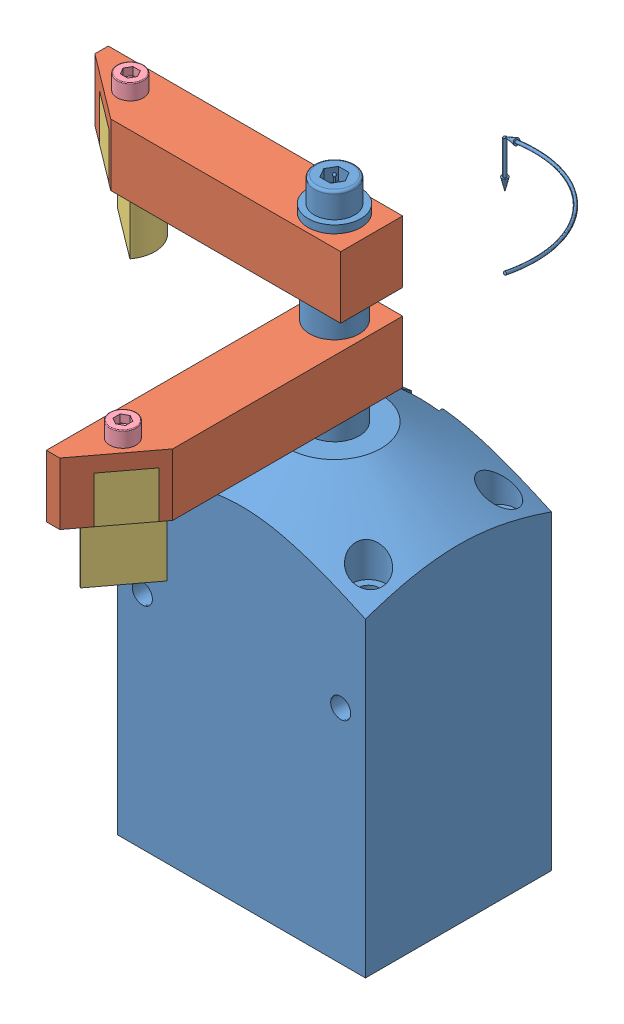
SolidWorks assembly assemb_pneu_clamp_v2, configuration Default. Lengths in mm.
Overall size (138.53 190.01 139).
9 component instances, 4 part files, 6 mates.
Components (placement in the parent):
- clamping_body_ccw-1: clamping_body_ccw [Default] at (55.286 179.8503 172.3742) x (-1 0 0) z (0 1 0) size (95.58 86.05 190.01)
- assemb_braco_v2-1: assemb_braco_v2 [Default] at (45.4961 98.2616 242.6188) x (-1 0 0) z (0 0 -1) size (95 45 24)
  - clamping_arm_sp_v2-1: clamping_arm_sp_v2 [Default] at (-9.7899 71.0887 70.2446) x (1 0 0) z (0 1 0) size (95 20 20)
  - contact_end_spec-1: contact_end_spec [Default] at (58.2101 31.0887 70.2446) x (0.601815 0 -0.798636) z (0.798636 0 0.601815) size (14.5 35 20)
  - socket head cap screw_iso-1: socket head cap screw_iso [ISO 4762 M5 x 12 - 12N] at (57.3074 76.0887 71.4426) x (0 -1 0) z (0 0 1) size (17 8.5 8.5)
- assemb_braco_v2-2: assemb_braco_v2 [Default] at (125.5306 68.2616 182.1641) x (0 0 1) z (-1 0 0) size (95 45 24)
  - clamping_arm_sp_v2-1: clamping_arm_sp_v2 [Default] at (-9.7899 71.0887 70.2446) x (1 0 0) z (0 1 0) size (95 20 20)
  - contact_end_spec-1: contact_end_spec [Default] at (58.2101 31.0887 70.2446) x (0.601815 0 -0.798636) z (0.798636 0 0.601815) size (14.5 35 20)
  - socket head cap screw_iso-1: socket head cap screw_iso [ISO 4762 M5 x 12 - 12N] at (57.3074 76.0887 71.4426) x (0 -1 0) z (0 0 1) size (17 8.5 8.5)
Mates (geometry in assembly coordinates):
- Concentric1: concentric aligned: cone of clamping_body_ccw-1 through (55.286 167.3503 172.3742) axis (0 1 0); cone of assemb_braco_v2-1/clamping_arm_sp_v2-1 through (55.286 169.3503 172.3742) axis (0 1 0)
- Parallel1: parallel aligned: plane of clamping_body_ccw-1 through (15.286 110.8503 142.3742) normal (-1 0 0); plane of assemb_braco_v2-1/clamping_arm_sp_v2-1 through (-27.714 149.3503 182.3742) normal (-1 0 0)
- Coincident2: coincident aligned: circle of clamping_body_ccw-1; plane of assemb_braco_v2-1/clamping_arm_sp_v2-1 through (67.286 149.3503 162.3742) normal (0 -1 0)
- Concentric2: concentric anti-aligned: cylinder of clamping_body_ccw-1 through (55.286 109.8716 172.3742) axis (0 -1 0) radius 8; cone of assemb_braco_v2-2/clamping_arm_sp_v2-1 through (55.286 139.3503 172.3742) axis (0 1 0)
- Parallel3: parallel aligned: plane of clamping_body_ccw-1 through (95.286 110.8503 202.3742) normal (0 0 1); plane of assemb_braco_v2-2/clamping_arm_sp_v2-1 through (65.286 119.3503 255.3742) normal (0 0 1)
- Distance2: distance = 30 mm aligned: plane of assemb_braco_v2-2/clamping_arm_sp_v2-1 through (45.286 139.3503 160.3742) normal (0 1 0); plane of assemb_braco_v2-1/clamping_arm_sp_v2-1 through (67.286 169.3503 162.3742) normal (0 1 0)
